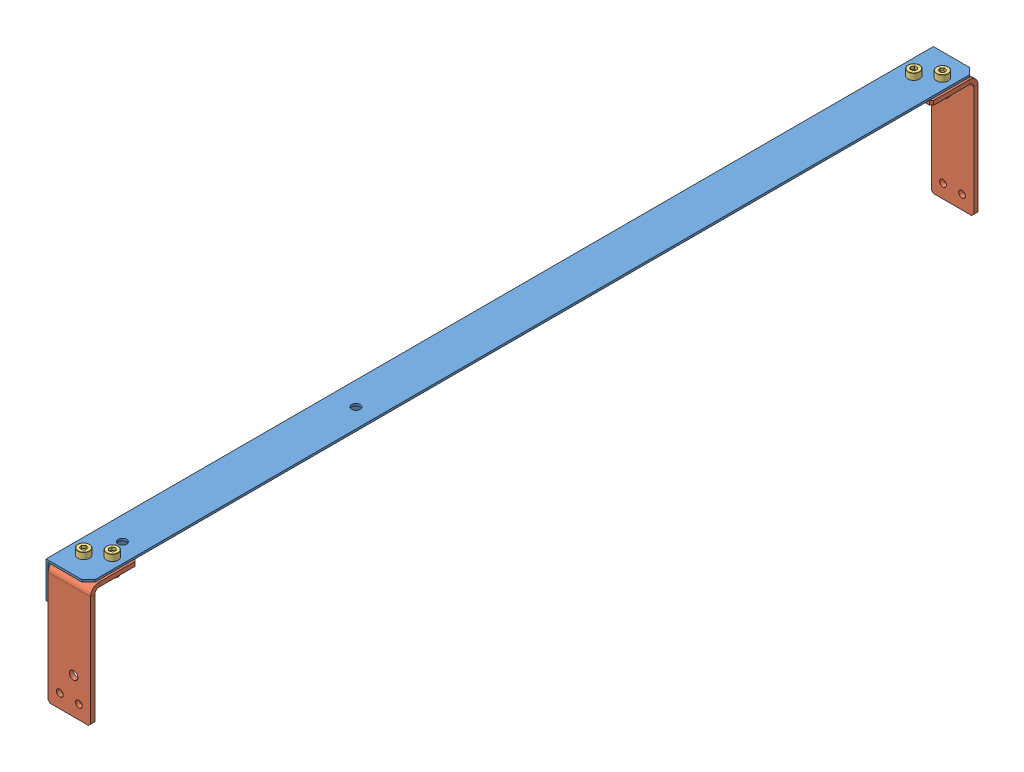
SolidWorks assembly CableChainMountFrameY, configuration Cable Chain Mount Frame Y. Lengths in mm.
Overall size (21 75.5 418).
11 component instances, 4 part files, 22 mates.
Components (placement in the parent):
- FrameBaseY-1: FrameBaseY [Frame Base Y] at (-54.5993 430.6623 409) x (1 0 0) z (0 0 -1) size (20 20 418)
- FrameBaseMountBracketY-5: FrameBaseMountBracketY [Frame Base Mount Bracket Y With Hole] at (-33.5993 448.2185 409) x (0 -1 0) z (0 0 -1) size (56.94 20 21.84)
- FrameBaseMountBracketY-4: FrameBaseMountBracketY [Frame Base Mount Bracket Y Without Hole] at (-53.5993 448.2185 -9) x (0 -1 0) z (0 0 1) size (75.5 20 21.84)
- socket head cap screw_iso-1: socket head cap screw_iso [ISO 4762 M3 x 8 - 8N] at (-39.8493 433.6623 1.5) x (0 -1 0) z (-0.778065 0 -0.628184) size (11 5.5 5.5)
- socket head cap screw_iso-2: socket head cap screw_iso [ISO 4762 M3 x 8 - 8N] at (-47.3493 433.6623 7.5) x (0 -1 0) z (-0.886112 0 -0.463471) size (11 5.5 5.5)
- socket head cap screw_iso-5: socket head cap screw_iso [ISO 4762 M3 x 8 - 8N] at (-47.3493 433.6623 398.5) x (0 -1 0) z (0.973174 0 -0.230071) size (11 5.5 5.5)
- socket head cap screw_iso-6: socket head cap screw_iso [ISO 4762 M3 x 8 - 8N] at (-39.8493 433.6623 392.5) x (0 -1 0) z (-0.356106 0 -0.934446) size (11 5.5 5.5)
- Nyloc nut St_Steel A2 ISO M2_5-M36-1: Nyloc nut St_Steel A2 ISO M2_5-M36 [M3 NYLOC DIN 985] at (-39.8493 427.6623 392.5) x (-0.769703 0 -0.638402) z (-0.638402 0 0.769703) size (6.35 4 5.5)
- Nyloc nut St_Steel A2 ISO M2_5-M36-2: Nyloc nut St_Steel A2 ISO M2_5-M36 [M3 NYLOC DIN 985] at (-47.3493 427.6623 398.5) x (0.676747 0 0.736216) z (0.736216 0 -0.676747) size (6.35 4 5.5)
- Nyloc nut St_Steel A2 ISO M2_5-M36-3: Nyloc nut St_Steel A2 ISO M2_5-M36 [M3 NYLOC DIN 985] at (-39.8493 427.6623 1.5) x (-0.740433 0 0.67213) z (0.67213 0 0.740433) size (6.35 4 5.5)
- Nyloc nut St_Steel A2 ISO M2_5-M36-4: Nyloc nut St_Steel A2 ISO M2_5-M36 [M3 NYLOC DIN 985] at (-47.3493 427.6623 7.5) x (0.979374 0 -0.202055) z (-0.202055 0 -0.979374) size (6.35 4 5.5)
Mates (geometry in assembly coordinates):
- Coincident228: coincident anti-aligned: plane of FrameBaseY-1 through (-34.5993 429.6623 -9) normal (0 -1 0); plane of FrameBaseMountBracketY-5 through (-33.5993 429.6623 387.1562) normal (0 1 0)
- Coincident229: coincident aligned: plane of FrameBaseY-1 through (-54.5993 430.6623 409) normal (0 0 1); plane of FrameBaseMountBracketY-5 through (-33.5993 448.2185 409) normal (0 0 1)
- Coincident230: coincident anti-aligned: plane of FrameBaseY-1 through (-53.5993 429.6623 -9) normal (1 0 0); plane of FrameBaseMountBracketY-5 through (-53.5993 448.2185 407) normal (-1 0 0)
- Coincident237: coincident anti-aligned: plane of FrameBaseY-1 through (-54.5993 430.6623 -9) normal (0 1 0); plane of socket head cap screw_iso-1 through (-41.5768 430.6623 3.6397) normal (0 -1 0)
- Coincident236: coincident anti-aligned: plane of FrameBaseY-1 through (-54.5993 430.6623 -9) normal (0 1 0); plane of socket head cap screw_iso-2 through (-48.6239 430.6623 9.9368) normal (0 -1 0)
- Coincident235: coincident anti-aligned: plane of socket head cap screw_iso-5 through (-47.982 430.6623 395.8238) normal (0 -1 0); plane of FrameBaseY-1 through (-54.5993 430.6623 -9) normal (0 1 0)
- Concentric143: concentric aligned: cylinder of socket head cap screw_iso-5 through (-47.3493 465.4123 398.5) axis (0 1 0) radius 1.5; cylinder of FrameBaseMountBracketY-5 through (-47.3493 429.6623 398.5) axis (0 1 0) radius 1.6
- Coincident234: coincident anti-aligned: plane of socket head cap screw_iso-6 through (-42.4191 430.6623 393.4793) normal (0 -1 0); plane of FrameBaseY-1 through (-54.5993 430.6623 -9) normal (0 1 0)
- Coincident241: coincident anti-aligned: plane of FrameBaseY-1 through (-34.5993 429.6623 -9) normal (0 -1 0); plane of FrameBaseMountBracketY-4 through (-53.5993 429.6623 12.8438) normal (0 1 0)
- Coincident242: coincident aligned: plane of FrameBaseY-1 through (-54.5993 430.6623 -9) normal (0 0 -1); plane of FrameBaseMountBracketY-4 through (-53.5993 448.2185 -9) normal (0 0 -1)
- Coincident243: coincident anti-aligned: plane of FrameBaseY-1 through (-53.5993 429.6623 -9) normal (1 0 0); plane of FrameBaseMountBracketY-4 through (-53.5993 448.2185 -7) normal (-1 0 0)
- Concentric156: concentric anti-aligned: cylinder of FrameBaseY-1 through (-39.8493 429.6623 1.5) axis (0 -1 0) radius 1.6; cylinder of socket head cap screw_iso-1 through (-39.8493 465.4123 1.5) axis (0 1 0) radius 1.5
- Concentric157: concentric aligned: cylinder of FrameBaseMountBracketY-4 through (-47.3493 429.6623 7.5) axis (0 1 0) radius 1.6; cylinder of socket head cap screw_iso-2 through (-47.3493 465.4123 7.5) axis (0 1 0) radius 1.5
- Coincident246: coincident anti-aligned: plane of FrameBaseMountBracketY-5 through (-33.5993 427.6623 387.1562) normal (0 -1 0); plane of Nyloc nut St_Steel A2 ISO M2_5-M36-1 through (-42.2935 427.6623 390.4728) normal (0 1 0)
- Concentric1611: concentric anti-aligned: cylinder of FrameBaseMountBracketY-5 through (-47.3493 429.6623 398.5) axis (0 1 0) radius 1.6; cylinder of Nyloc nut St_Steel A2 ISO M2_5-M36-2 through (-47.3493 427.6623 398.5) axis (0 -1 0) radius 1.195
- Coincident2471: coincident anti-aligned: plane of FrameBaseMountBracketY-5 through (-33.5993 427.6623 387.1562) normal (0 -1 0); plane of Nyloc nut St_Steel A2 ISO M2_5-M36-2 through (-45.2004 427.6623 400.8378) normal (0 1 0)
- Concentric1621: concentric anti-aligned: cylinder of FrameBaseMountBracketY-4 through (-39.8493 429.6623 1.5) axis (0 1 0) radius 1.6; cylinder of Nyloc nut St_Steel A2 ISO M2_5-M36-3 through (-39.8493 427.6623 1.5) axis (0 -1 0) radius 1.195
- Coincident2481: coincident anti-aligned: plane of FrameBaseMountBracketY-4 through (-53.5993 427.6623 12.8438) normal (0 -1 0); plane of Nyloc nut St_Steel A2 ISO M2_5-M36-3 through (-42.2005 427.6623 3.6343) normal (0 1 0)
- Concentric1631: concentric anti-aligned: cylinder of FrameBaseMountBracketY-4 through (-47.3493 429.6623 7.5) axis (0 1 0) radius 1.6; cylinder of Nyloc nut St_Steel A2 ISO M2_5-M36-4 through (-47.3493 427.6623 7.5) axis (0 -1 0) radius 1.195
- Coincident2491: coincident anti-aligned: plane of FrameBaseMountBracketY-4 through (-53.5993 427.6623 12.8438) normal (0 -1 0); plane of Nyloc nut St_Steel A2 ISO M2_5-M36-4 through (-44.2394 427.6623 6.8584) normal (0 1 0)
- Concentric1632: concentric anti-aligned: cylinder of FrameBaseY-1 through (-39.8493 429.6623 392.5) axis (0 -1 0) radius 1.6; cylinder of socket head cap screw_iso-6 through (-39.8493 465.4123 392.5) axis (0 1 0) radius 2.75
- Concentric1633: concentric aligned: cylinder of FrameBaseMountBracketY-5 through (-39.8493 429.6623 392.5) axis (0 1 0) radius 1.6; cylinder of Nyloc nut St_Steel A2 ISO M2_5-M36-1 through (-39.8493 423.6623 392.5) axis (0 1 0) radius 2.75
